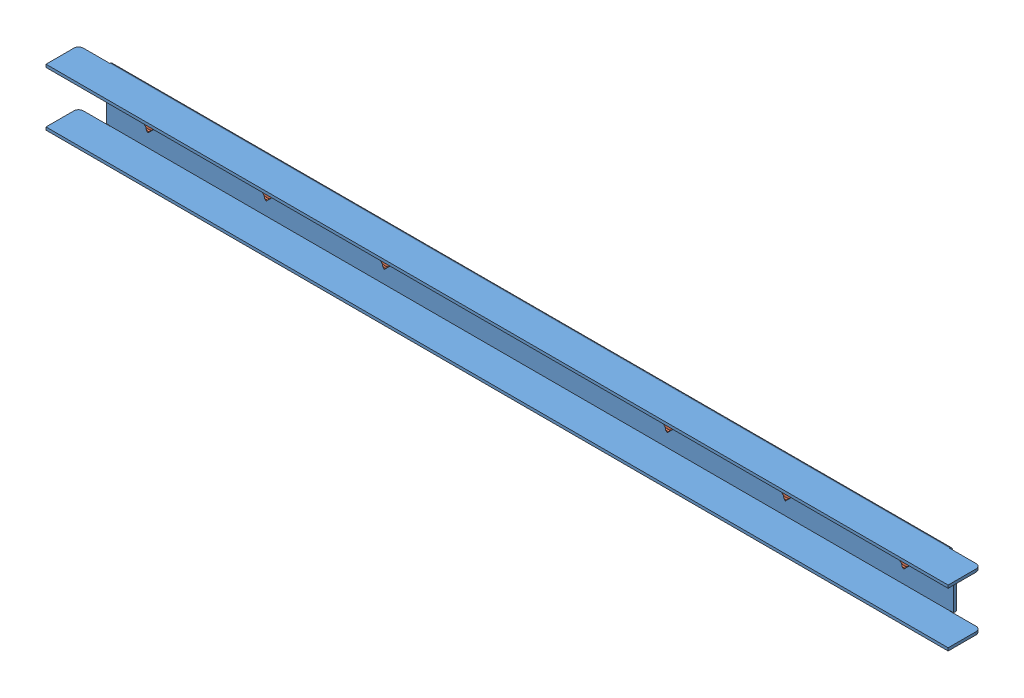
SolidWorks assembly 機體-補強1, configuration 預設. Lengths in mm.
Overall size (954 60.44 38.15).
7 component instances, 2 part files, 5 mates.
Components (placement in the parent):
- LB-A54A-02-43-1: LB-A54A-02-43 [預設] at (-445.6157 -48.5473 -18.86) size (954 60.44 37.72)
- 2分半點焊螺帽-1: 2分半點焊螺帽 [預設] at (-368.1832 13.9527 -11.36) x (1 0 0) z (0 1 0) size (18.22 7.93 18.22)
- 2分半點焊螺帽-2: 2分半點焊螺帽 [預設] at (-243.1832 13.9527 -11.36) x (1 0 0) z (0 1 0) size (18.22 7.93 18.22)
- 2分半點焊螺帽-3: 2分半點焊螺帽 [預設] at (-118.1832 13.9527 -11.36) x (1 0 0) z (0 1 0) size (18.22 7.93 18.22)
- 2分半點焊螺帽-4: 2分半點焊螺帽 [預設] at (430.9519 13.9527 -11.36) x (1 0 0) z (0 1 0) size (18.22 7.93 18.22)
- 2分半點焊螺帽-5: 2分半點焊螺帽 [預設] at (305.9519 13.9527 -11.36) x (1 0 0) z (0 1 0) size (18.22 7.93 18.22)
- 2分半點焊螺帽-6: 2分半點焊螺帽 [預設] at (180.9519 13.9527 -11.36) x (1 0 0) z (0 1 0) size (18.22 7.93 18.22)
Mates (geometry in assembly coordinates):
- 同軸心1: concentric aligned: cylinder of 2分半點焊螺帽-1 through (-368.1832 13.9527 -21.3282) axis (0 0 -1) radius 6.5; cylinder of LB-A54A-02-43-1 through (-368.1832 13.9527 -15.86) axis (0 0 -1) radius 6.6
- 重合/共線/共點1: coincident aligned: plane of LB-A54A-02-43-1 through (503.3843 46.9527 -18.86) normal (0 0 -1); plane of 2分半點焊螺帽-1 through (-368.1832 4.7603 -18.86) normal (0 0 -1)
- 同軸心2: concentric aligned: cylinder of 2分半點焊螺帽-4 through (430.9519 13.9527 -21.3282) axis (0 0 -1) radius 6.5; cylinder of LB-A54A-02-43-1 through (430.9519 13.9527 -15.86) axis (0 0 -1) radius 6.6
- 重合/共線/共點2: coincident aligned: plane of LB-A54A-02-43-1 through (503.3843 46.9527 -18.86) normal (0 0 -1); plane of 2分半點焊螺帽-4 through (430.9519 4.7603 -18.86) normal (0 0 -1)
- 局部直線複製2: unknown: line of LB-A54A-02-43-1 through (-412.6157 41.1727 -18.86) axis (1 0 0)
